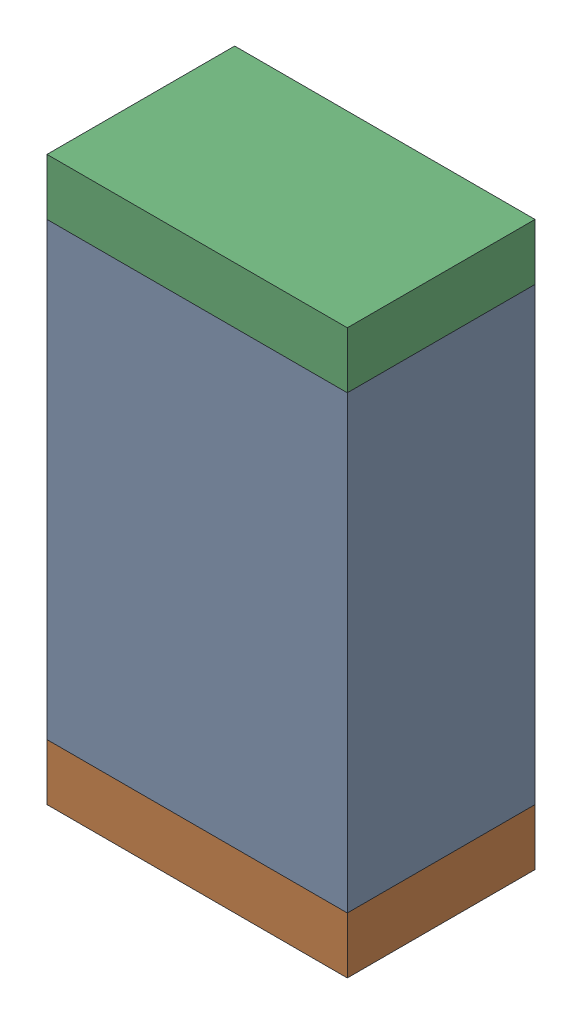
SolidWorks assembly R54, configuration Default. Lengths in mm.
Overall size (0.8 1.5 0.5).
6 component instances, 2 part files, 0 mates.
Components (placement in the parent):
- 810156976-1: 810156976 [Default] at (114 63.3 0) size (0.8 1.2 0.5)
  - Extruded_6-1: Extruded_6 [Default] at origin size (0.8 1.2 0.5)
- 810156592-1: 810156592 [Default] at (114 62.625 0) size (0.8 0.15 0.5)
  - Extruded_7-1: Extruded_7 [Default] at origin size (0.8 0.15 0.5)
- 810156592-2: 810156592 [Default] at (114 63.975 0) size (0.8 0.15 0.5)
  - Extruded_7-1: Extruded_7 [Default] at origin size (0.8 0.15 0.5)
